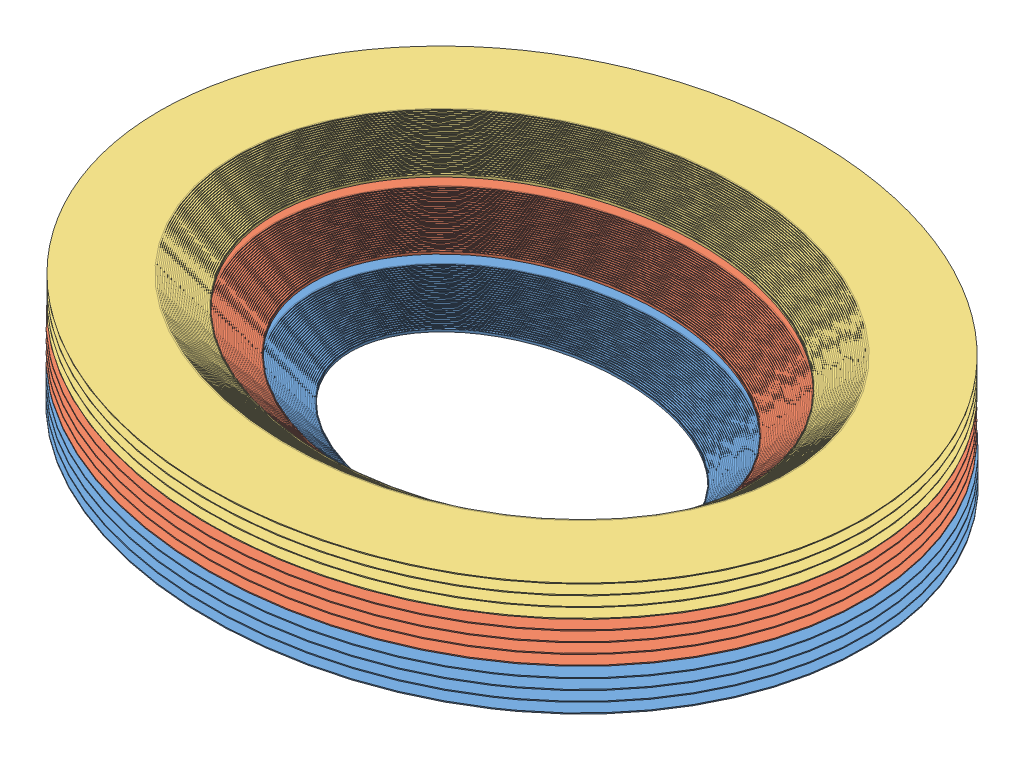
SolidWorks assembly stairs assembly, configuration Default. Lengths in mm.
Overall size (362092.83 64008.01 310883.56).
3 component instances, 3 part files, 4 mates.
Components (placement in the parent):
- stairs-1: stairs [Base stair] at (22363.6696 118336.3599 214645.2232) size (360558.09 15748.05 310585.91)
- middle stairs-1: middle stairs [Base stair] at (3250.1696 138656.3599 214645.2232) size (335367.35 15748.06 286294.91)
- top stairs-1: top stairs [Base stair] at (-15228.3304 158976.3599 214645.2232) size (362092.83 40259 310050.05)
Mates (geometry in assembly coordinates):
- Coincident3: coincident anti-aligned: plane of stairs-1 through (22363.6696 138656.3599 214645.2232) normal (0 1 0); plane of middle stairs-1 through (22960.5696 138656.3599 214645.2232) normal (0 -1 0)
- Coincident4: coincident: point of middle stairs-1; line of assembly
- Coincident5: coincident anti-aligned: plane of middle stairs-1 through (3250.1696 158976.3599 214645.2232) normal (0 1 0); plane of top stairs-1 through (-15228.3304 158976.3599 214645.2232) normal (0 -1 0)
- Coincident6: coincident: point of top stairs-1; line of assembly
